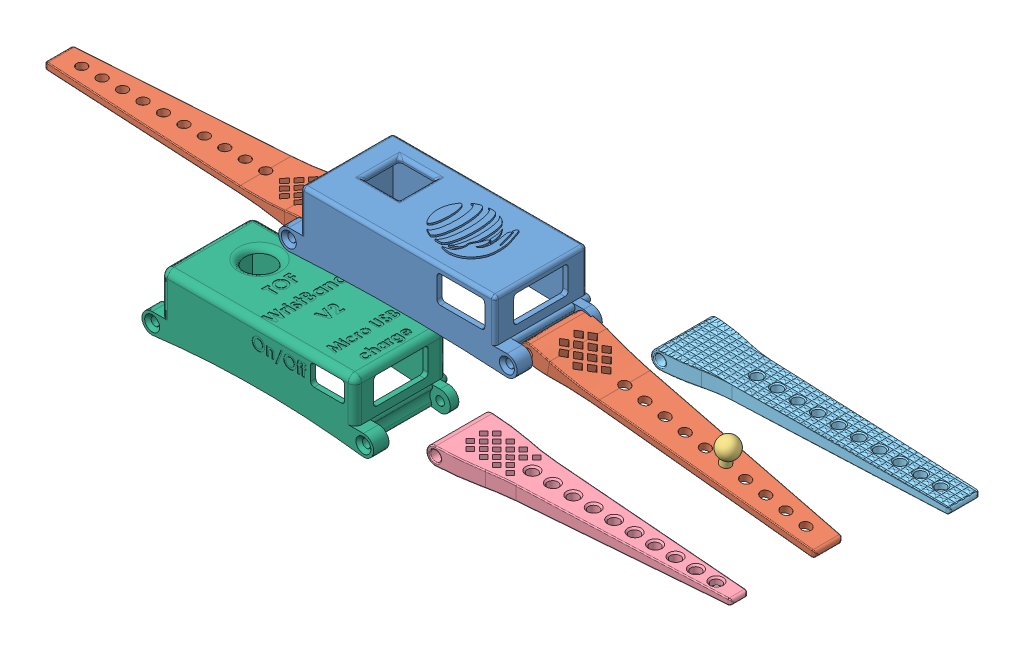
SolidWorks assembly TOF system test 1, configuration Default. Lengths in mm.
Overall size (251.29 41.7 56.18).
7 component instances, 6 part files, 4 mates.
Components (placement in the parent):
- body1-1: body1 [Default] at origin size (70 19 27)
- Cinturino_1A-1: Cinturino_1A [Default] at (32 3 -1.2195) x (0.985157 -0.171655 0) z (0 0 1) size (83.5 5 17.02)
- Cinturino_1A-2: Cinturino_1A [Default] at (-32 3 0.2751) x (-0.999966 -0.008226 0) z (0 0 -1) size (83.5 5 17.02)
- PernoChiusura-1: PernoChiusura [Default] at (80.9145 -7.5531 -1.2195) x (0.167498 -0.029185 0.98544) z (-0.171655 -0.985157 0) size (5.91 5.91 10.5)
- Cinturino_2B-1: Cinturino_2B [Default] at (21.4085 -20.1462 15.4928) size (83.66 5.1 17)
- Cinturino_3a-1: Cinturino_3a [Default] at (57.1618 6.9776 -14.6565) size (83.66 5.14 17)
- body1z-1: body1z [Default] at (-21.5764 -21.81 19.5274) size (68 18.5 27)
Mates (geometry in assembly coordinates):
- Concentric1: concentric aligned: circle of body1-1; cylinder of Cinturino_1A-1 through (32 3 7.2805) axis (0 0 -1) radius 1.25
- Concentric2: concentric aligned: circle of body1-1; cylinder of Cinturino_1A-2 through (-32 3 -8.2249) axis (0 0 1) radius 1.25
- Concentric3: concentric anti-aligned: circle of Cinturino_1A-1; cylinder of PernoChiusura-1 through (80.9145 -7.5531 -1.2195) axis (-0.171655 -0.985157 0) radius 1.5
- Coincident1: coincident aligned: plane of Cinturino_1A-1 through (51.5315 -1.4183 7.2805) normal (-0.171655 -0.985157 0); circle of PernoChiusura-1
